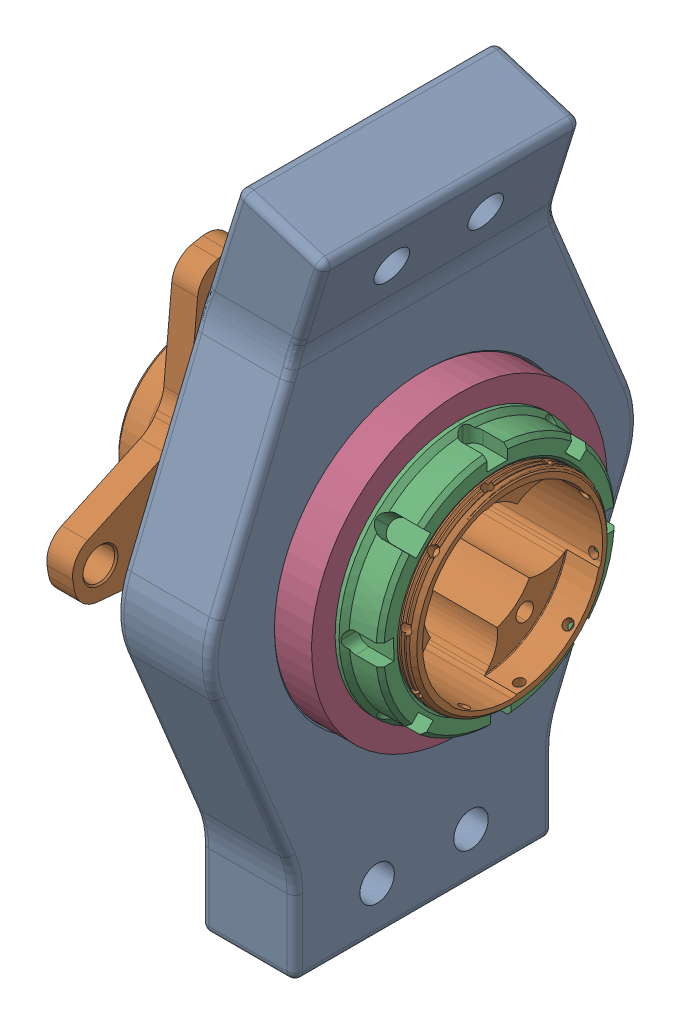
SolidWorks assembly Rear Wheel Assembly, configuration Default. Lengths in mm.
Overall size (101.92 211.1 136.73).
5 component instances, 4 part files, 8 mates.
Components (placement in the parent):
- 230013-1: 230013 [Default] at origin size (38.73 211.1 136.73)
- 230014-1: 230014 [Default] at (43.1025 0 0) x (-1 0 0) z (0 0.985491 0.169729) size (101.92 117.35 117.35)
- 230015-1: 230015 [Default] at (38.975 0 0) x (-1 0 0) z (0 -0.999879 -0.015564) size (12.7 79.38 79.38)
- 230016-1: 230016 [Default] at (16.75 0 0) x (1 0 0) z (0 0.227438 0.973792) size (19.05 94.42 94.42)
- 230016-2: 230016 [Default] at (-16.75 0 0) x (1 0 0) z (0 0.227438 0.973792) size (19.05 94.42 94.42)
Mates (geometry in assembly coordinates):
- Concentric1: concentric aligned: cylinder of WheelKnuckle_Back-1 through (-15 0 0) axis (1 0 0) radius 47.3122; cylinder of D5580.step-1 through (43.1025 0 0) axis (1 0 0) radius 31.75
- Coincident1: coincident anti-aligned: plane of WheelKnuckle_Back-1 through (-15 0 0) normal (-1 0 0); plane of D5580.step-1 through (-15 -5.6476 32.7912) normal (1 0 0)
- Screw1: screw = 1 aligned: cylinder of D5580.step-1 through (43.1025 0 0) axis (1 0 0) radius 31.6865; cylinder of D5239.step-1 through (38.975 0 0) axis (1 0 0) radius 31.242
- Tangent1: tangent anti-aligned: cylinder of D5580.step-1 through (40.5625 34.4497 -65.417) axis (0 -0.465955 0.884808) radius 1.5875; plane of D5239.step-1 through (38.975 0.506 -32.5081) normal (1 0 0)
- Concentric2: concentric anti-aligned: cylinder of D5580.step-1 through (43.1025 0 0) axis (1 0 0) radius 31.75; cylinder of Rear Ball Bearing (L610549)-1 through (26.275 0 0) axis (-1 0 0) radius 47.2122
- Coincident2: coincident anti-aligned: plane of D5239.step-1 through (26.275 0.6177 -39.6827) normal (-1 0 0); plane of Rear Ball Bearing (L610549)-1 through (26.275 0 0) normal (1 0 0)
- Concentric3: concentric anti-aligned: cylinder of D5580.step-1 through (43.1025 0 0) axis (1 0 0) radius 31.75; cylinder of Rear Ball Bearing (L610549)-2 through (-7.225 0 0) axis (-1 0 0) radius 31.75
- Width1: width anti-aligned: plane of Rear Ball Bearing (L610549)-1 through (26.275 0 0) normal (1 0 0); plane of WheelKnuckle_Back-1 through (-26.275 0 0) normal (-1 0 0); plane of Rear Ball Bearing (L610549)-2 through (-15 0 0) normal (-1 0 0); plane of WheelKnuckle_Back-1 through (15 0 0) normal (1 0 0)
